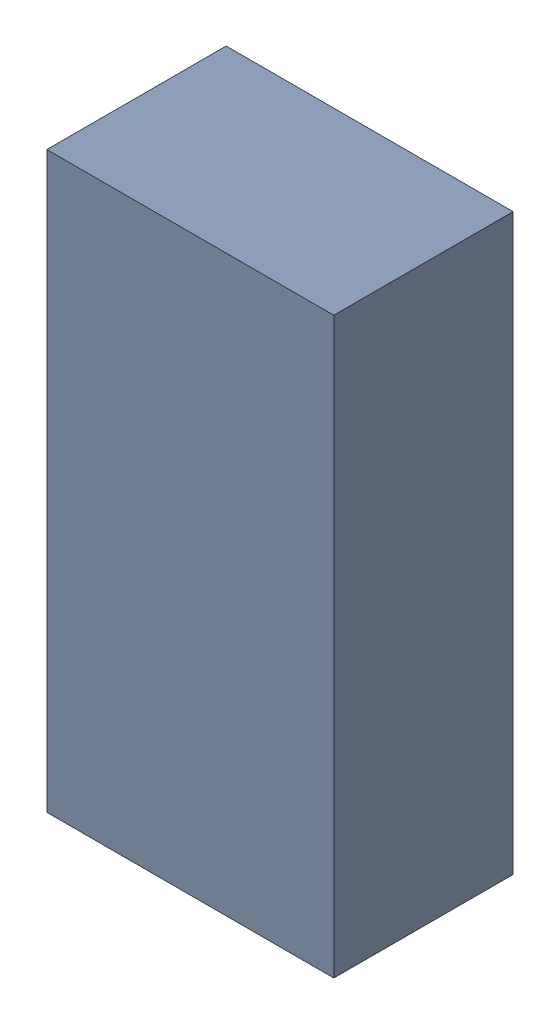
SolidWorks assembly R300_2PCB, configuration Default. Lengths in mm.
Overall size (1.6 3.2 1).
2 component instances, 1 part files, 0 mates.
Components (placement in the parent):
- 846485328-1: 846485328 [Default] at (156.2753 97.618 0) size (1.6 3.2 1)
  - Extruded_34-1: Extruded_34 [Default] at origin size (1.6 3.2 1)
